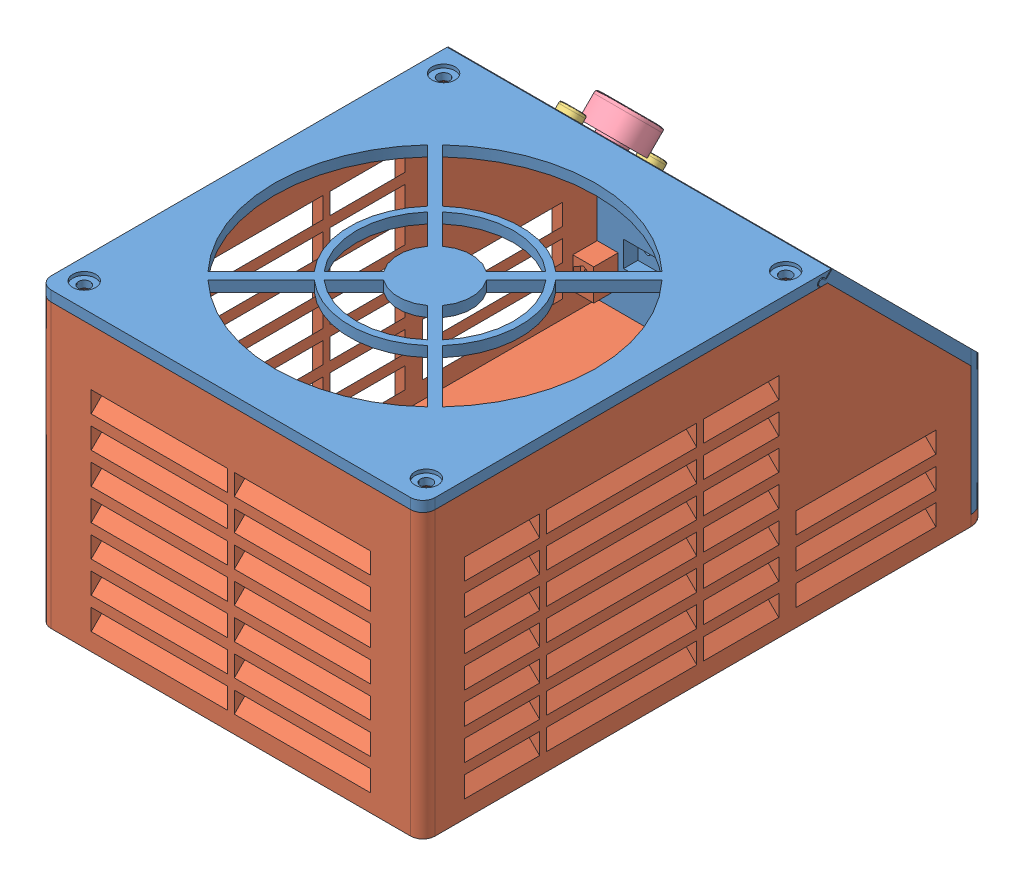
SolidWorks assembly 装配体, configuration 默认. Lengths in mm.
Overall size (110 84 161.95).
5 component instances, 4 part files, 8 mates.
Components (placement in the parent):
- 上壳-1: 上壳 [默认] at (-112.9925 -31.2187 22.7561) size (110 81 161.95)
- 下壳-1: 下壳 [默认] at (-112.9925 -34.2158 -0.2506) size (110 81 161.95)
- 按键帽-1: 按键帽 [默认] at (-143.2925 38.1215 -44.5831) x (1 0 0) z (0 0.707107 0.707107) size (7.5 4.5 7.5)
- 旋钮帽-1: 旋钮帽 [默认] at (-143.2925 27.3381 -58.3363) x (0.995941 -0.063645 -0.063645) z (0.090007 0.704237 0.704237) size (16 7.6 16)
- 按键帽-2: 按键帽 [默认] at (-143.2925 15.0344 -67.6701) x (0.999165 0.028884 0.028884) z (-0.040848 0.706517 0.706517) size (7.5 4.5 7.5)
Mates (geometry in assembly coordinates):
- 重合1: coincident aligned: plane of 上壳-1 through (-57.9925 49.7835 80.7261) normal (0 0 1); plane of 下壳-1 through (-167.9925 -31.2158 80.7261) normal (0 0 1)
- 重合2: coincident aligned: plane of 上壳-1 through (-57.9925 -31.2187 22.7561) normal (1 0 0); plane of 下壳-1 through (-57.9925 -31.2158 80.7261) normal (1 0 0)
- 同心1: concentric aligned: cylinder of 上壳-1 through (-143.2925 62.274 -68.7356) axis (0 -0.707107 0.707107) radius 3.25; cylinder of 按键帽-1 through (-143.2925 38.7579 -45.2195) axis (0 -0.707107 0.707107) radius 3.15
- 同心2: concentric anti-aligned: cylinder of 上壳-1 through (-143.2925 50.0057 -81.0039) axis (0 -0.707107 0.707107) radius 4.75; cylinder of 旋钮帽-1 through (-143.2925 32.9949 -63.9931) axis (0 0.707107 -0.707107) radius 8
- 重合3: coincident anti-aligned: plane of 上壳-1 through (-57.9925 48.7229 -35.3959) normal (0 -0.707107 0.707107); plane of 按键帽-1 through (-140.1425 38.8286 -45.2902) normal (0 0.707107 -0.707107)
- 重合4: coincident anti-aligned: plane of 上壳-1 through (-57.9925 49.7835 -36.4565) normal (0 0.707107 -0.707107); plane of 旋钮帽-1 through (-139.4083 27.3727 -58.8674) normal (0 -0.707107 0.707107)
- 同心3: concentric aligned: cylinder of 上壳-1 through (-143.2925 39.187 -91.8226) axis (0 -0.707107 0.707107) radius 3.25; cylinder of 按键帽-2 through (-143.2925 15.6708 -68.3065) axis (0 -0.707107 0.707107) radius 3.15
- 重合5: coincident anti-aligned: plane of 上壳-1 through (-57.9925 48.7229 -35.3959) normal (0 -0.707107 0.707107); plane of 按键帽-2 through (-140.1451 15.8325 -68.2862) normal (0 0.707107 -0.707107)
